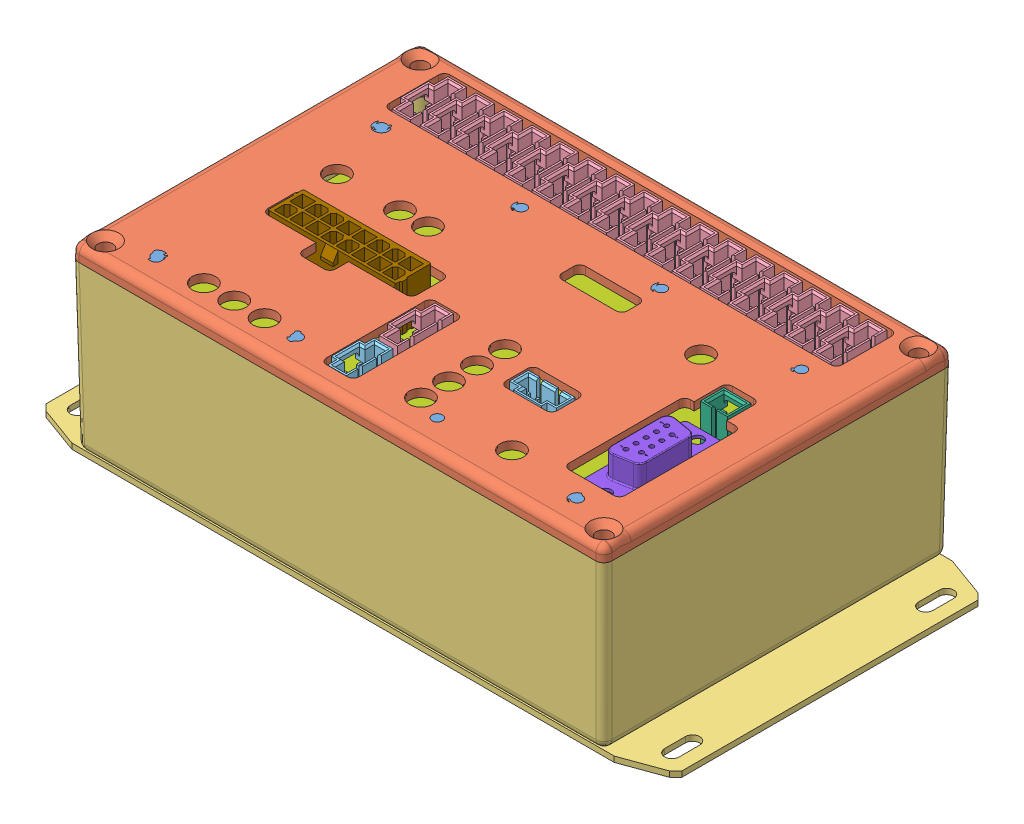
SolidWorks assembly AMS, configuration Default. Lengths in mm.
Overall size (172.97 52.31 95).
35 component instances, 9 part files, 0 mates.
Components (placement in the parent):
- 1590J Lid - Modified-1: 1590J Lid - Modified [Default] at (0 46.5 0) size (145 6.56 95)
  - PEM FHS-440-4ZI-1: PEM FHS-440-4ZI [Default] at (57.15 4 -21.59) x (0 -1 0) z (0 0 1) size (6.35 4.47 4.47)
  - PEM FHS-440-4ZI-2: PEM FHS-440-4ZI [Default] at (-19.05 4 -21.59) x (0 -1 0) z (0 0 1) size (6.35 4.47 4.47)
  - 1590J Lid-1: 1590J Lid [Default] x (1 0 0) z (0 -1 0) size (145 95 6.25)
  - PEM FHS-440-4ZI-3: PEM FHS-440-4ZI [Default] at (57.15 4 39.37) x (0 -1 0) z (0 0 1) size (6.35 4.47 4.47)
  - PEM FHS-440-4ZI-4: PEM FHS-440-4ZI [Default] at (-57.15 4 -21.59) x (0 -1 0) z (0 0 1) size (6.35 4.47 4.47)
  - PEM FHS-440-4ZI-5: PEM FHS-440-4ZI [Default] at (19.05 4 -21.59) x (0 -1 0) z (0 0 1) size (6.35 4.47 4.47)
  - PEM FHS-440-4ZI-6: PEM FHS-440-4ZI [Default] at (-19.05 4 39.37) x (0 -1 0) z (0 0 1) size (6.35 4.47 4.47)
  - PEM FHS-440-4ZI-7: PEM FHS-440-4ZI [Default] at (19.05 4 39.37) x (0 -1 0) z (0 0 1) size (6.35 4.47 4.47)
  - PEM FHS-440-4ZI-8: PEM FHS-440-4ZI [Default] at (-57.15 4 39.37) x (0 -1 0) z (0 0 1) size (6.35 4.47 4.47)
- 1590JF Box-1: 1590JF Box [Default] at (0 46.5 0) x (1 0 0) z (0 1 0) size (172.97 95 46.5)
- Lithiumate Board Assy-1: Lithiumate Board Assy [Default] at (0 37.9813 0) size (127 17.25 88.9)
  - Molex 705430004-1: Molex 705430004 [Default] at (-34.417 6.8898 -34.7726) x (0 0 -1) z (0 1 0) size (15.24 6.6 15.11)
  - Molex 705430004-2: Molex 705430004 [Default] at (-26.797 6.8898 -34.7726) x (0 0 -1) z (0 1 0) size (15.24 6.6 15.11)
  - Molex 705430004-3: Molex 705430004 [Default] at (-42.037 6.8898 -34.7726) x (0 0 -1) z (0 1 0) size (15.24 6.6 15.11)
  - Molex 705430004-4: Molex 705430004 [Default] at (49.403 6.8898 -34.7726) x (0 0 -1) z (0 1 0) size (15.24 6.6 15.11)
  - Molex 705430004-5: Molex 705430004 [Default] at (-57.277 6.8898 -34.7726) x (0 0 -1) z (0 1 0) size (15.24 6.6 15.11)
  - Molex 705430003-1: Molex 705430003 [Default] at (-5.715 6.8898 35.56) x (0 0 -1) z (0 1 0) size (12.7 6.6 15.11)
  - Molex 705430004-6: Molex 705430004 [Default] at (-49.657 6.8898 -34.7726) x (0 0 -1) z (0 1 0) size (15.24 6.6 15.11)
  - Molex 705430004-7: Molex 705430004 [Default] at (-3.937 6.8898 -34.7726) x (0 0 -1) z (0 1 0) size (15.24 6.6 15.11)
  - Molex 705430004-8: Molex 705430004 [Default] at (41.783 6.8898 -34.7726) x (0 0 -1) z (0 1 0) size (15.24 6.6 15.11)
  - Molex 705430003-2: Molex 705430003 [Default] at (26.67 6.8898 18.415) x (-1 0 0) z (0 1 0) size (12.7 6.6 15.11)
  - Molex 705430004-9: Molex 705430004 [Default] at (34.163 6.8898 -34.7726) x (0 0 -1) z (0 1 0) size (15.24 6.6 15.11)
  - Molex 705430004-10: Molex 705430004 [Default] at (-11.557 6.8898 -34.7726) x (0 0 -1) z (0 1 0) size (15.24 6.6 15.11)
  - Molex 705430004-11: Molex 705430004 [Default] at (3.683 6.8898 -34.7726) x (0 0 -1) z (0 1 0) size (15.24 6.6 15.11)
  - Molex 705430001-1: Molex 705430001 [Default] at (54.6354 6.8898 -2.8448) x (1 0 0) z (0 1 0) size (7.37 6.35 15.11)
  - Molex 705430004-12: Molex 705430004 [Default] at (18.923 6.8898 -34.7726) x (0 0 -1) z (0 1 0) size (15.24 6.6 15.11)
  - Molex 705430004-13: Molex 705430004 [Default] at (-19.177 6.8898 -34.7726) x (0 0 -1) z (0 1 0) size (15.24 6.6 15.11)
  - Molex 705430004-14: Molex 705430004 [Default] at (57.023 6.8898 -34.7726) x (0 0 -1) z (0 1 0) size (15.24 6.6 15.11)
  - Molex 705430004-15: Molex 705430004 [Default] at (11.303 6.8898 -34.7726) x (0 0 -1) z (0 1 0) size (15.24 6.6 15.11)
  - Molex 705430004-16: Molex 705430004 [Default] at (26.543 6.8898 -34.7726) x (0 0 -1) z (0 1 0) size (15.24 6.6 15.11)
  - Lithiumate Board-1: Lithiumate Board [Default] at origin size (127 1.59 88.9)
  - NorComp 171-009-213-1: NorComp 171-009-213 [Default] at (61.5696 8.1852 32.6898) x (0 0 -1) z (0 1 0) size (30.81 12.6 17.25)
  - Molex 705430004-17: Molex 705430004 [Default] at (-5.715 6.8898 20.32) x (0 0 -1) z (0 1 0) size (15.24 6.6 15.11)
  - Molex 039281163-1: Molex 039281163 [Default] at (-34.5176 0.7937 9.6526) size (35.6 16.3 11)
